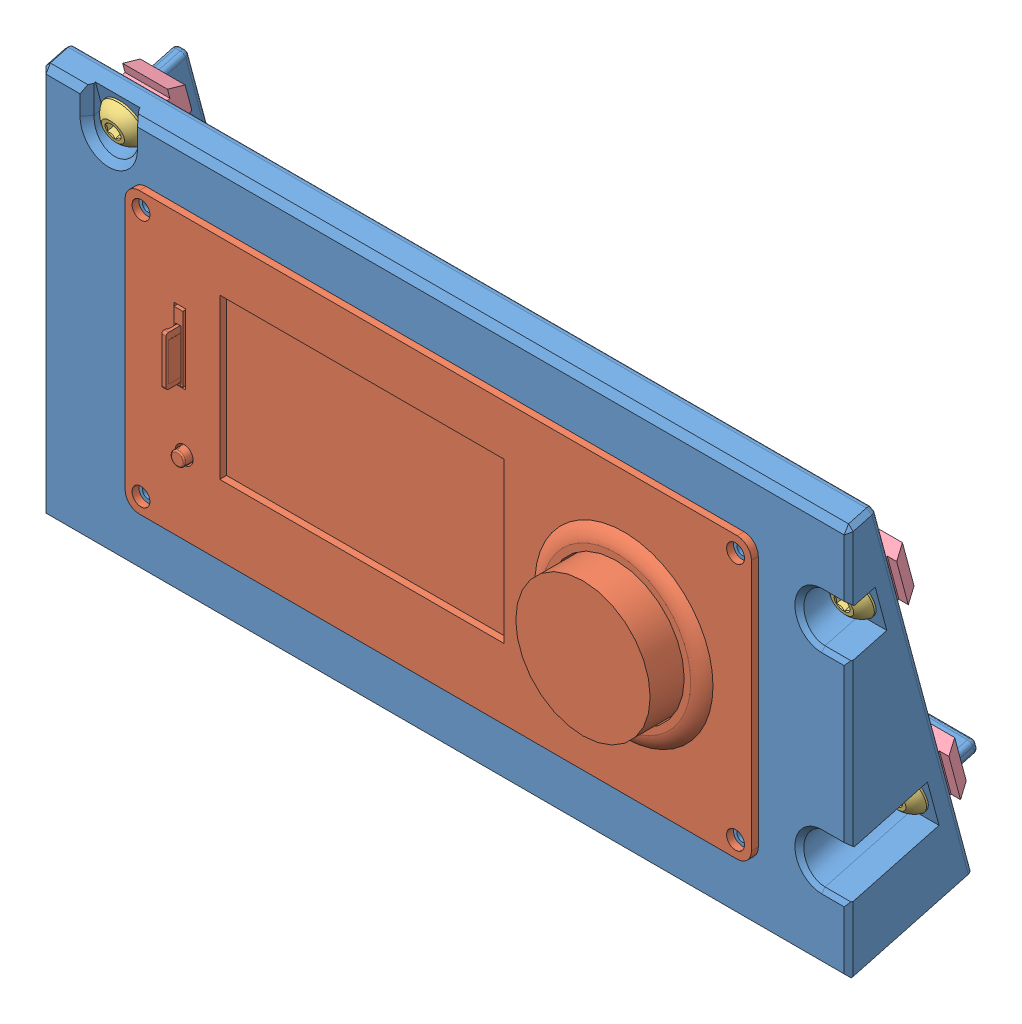
SolidWorks assembly Viki2_LCD_Module, configuration Default. Lengths in mm.
Overall size (180 89.23 58.16).
8 component instances, 4 part files, 18 mates.
Components (placement in the parent):
- Viki2_Mount-1: Viki2_Mount [Default] at origin size (180 88.55 48.84)
- Viki2_LCD-1: Viki2_LCD [Default] at (-111.8203 -17.9312 -4.239) x (1 0.00011 0) z (0 0 1) size (139.71 62.5 29.06)
- 5mmX10mm_Buttonhead(McMaster_91239A224)-1: 5mmX10mm_Buttonhead(McMaster_91239A224) [91239A224] at (-165 -6.7661 2.0693) x (1 0 0) z (0 -0.258819 0.965926) size (9.5 9.5 13.21)
- 5mmX10mm_Buttonhead(McMaster_91239A224)-2: 5mmX10mm_Buttonhead(McMaster_91239A224) [91239A224] at (-6 -20.2891 -1.5542) x (1 0 0) z (0 -0.258819 0.965926) size (9.5 9.5 13.21)
- 5mmX10mm_Buttonhead(McMaster_91239A224)-3: 5mmX10mm_Buttonhead(McMaster_91239A224) [91239A224] at (-6 -63.7572 -13.2014) x (1 0 0) z (0 -0.258819 0.965926) size (9.5 9.5 13.21)
- HNTTSN5-5-1: HNTTSN5-5 [Default] at (-165 -4.7085 -5.6098) x (0 -0.258819 0.965926) z (-1 0 0) size (4.3 10 10)
- HNTTSN5-5-2: HNTTSN5-5 [Default] at (-6 -18.2315 -9.2333) x (0 -0.258819 0.965926) z (0 0.965926 0.258819) size (4.3 10 10)
- HNTTSN5-5-3: HNTTSN5-5 [Default] at (-6 -61.6996 -20.8805) x (0 -0.258819 0.965926) z (0 0.965926 0.258819) size (4.3 10 10)
Mates (geometry in assembly coordinates):
- Coincident1: coincident anti-aligned: plane of Viki2_Mount-1 through (0 0 3) normal (0 0 1); plane of Viki2_LCD-1 through (-20.15 -75.242 3) normal (0 0 -1)
- Coincident2: coincident aligned: plane of Viki2_Mount-1 through (-90 0 0) normal (1 0 0); plane of Viki2_LCD-1
- Coincident3: coincident anti-aligned: plane of Viki2_Mount-1 through (0 -44 0) normal (0 1 0); plane of Viki2_LCD-1
- Concentric1: concentric aligned: cylinder of Viki2_Mount-1 through (-165 -3.1158 -11.554) axis (0 -0.258819 0.965926) radius 2.6; cylinder of 5mmX10mm_Buttonhead(McMaster_91239A224)-1 through (-165 -6.7661 2.0693) axis (0 -0.258819 0.965926) radius 4.75
- Coincident4: coincident anti-aligned: plane of Viki2_Mount-1 through (-165 -6.0544 -0.587) normal (0 -0.258819 0.965926); plane of 5mmX10mm_Buttonhead(McMaster_91239A224)-1 through (-165 -10.6425 -1.8164) normal (0 0.258819 -0.965926)
- Concentric2: concentric anti-aligned: cylinder of 5mmX10mm_Buttonhead(McMaster_91239A224)-1 through (-165 -6.7661 2.0693) axis (0 -0.258819 0.965926) radius 4.75; cylinder of HNTTSN5-5-1 through (-165 -4.7085 -5.6098) axis (0 0.258819 -0.965926) radius 2.067
- Parallel1: parallel aligned: plane of Viki2_Mount-1 through (-180 0 3) normal (-1 0 0); plane of HNTTSN5-5-1 through (-170 -4.7085 -5.6098) normal (-1 0 0)
- Distance1: distance = 2 mm anti-aligned: plane of Viki2_Mount-1 through (-3 -81.3287 -24.8978) normal (0 0.258819 -0.965926); plane of HNTTSN5-5-1 through (-170 -1.7003 -5.632) normal (0 -0.258819 0.965926)
- Concentric3: concentric aligned: cylinder of Viki2_Mount-1 through (-6 -16.6387 -15.1775) axis (0 -0.258819 0.965926) radius 2.6; cylinder of 5mmX10mm_Buttonhead(McMaster_91239A224)-2 through (-6 -20.2891 -1.5542) axis (0 -0.258819 0.965926) radius 4.75
- Coincident7: coincident anti-aligned: plane of Viki2_Mount-1 through (-6 -19.5773 -4.2105) normal (0 -0.258819 0.965926); plane of 5mmX10mm_Buttonhead(McMaster_91239A224)-2 through (-6 -24.1655 -5.4398) normal (0 0.258819 -0.965926)
- Concentric4: concentric anti-aligned: cylinder of 5mmX10mm_Buttonhead(McMaster_91239A224)-2 through (-6 -20.2891 -1.5542) axis (0 -0.258819 0.965926) radius 4.75; cylinder of HNTTSN5-5-2 through (-6 -18.2315 -9.2333) axis (0 0.258819 -0.965926) radius 2.067
- Perpendicular1: perpendicular: plane of Viki2_Mount-1 through (0 0 3) normal (1 0 0); plane of HNTTSN5-5-2 through (-6 -23.0611 -10.5274) normal (0 -0.965926 -0.258819)
- Distance2: distance = 2 mm anti-aligned: plane of HNTTSN5-5-2 through (-3.1 -13.1948 -8.7119) normal (0 -0.258819 0.965926); plane of Viki2_Mount-1 through (-3 -81.3287 -24.8978) normal (0 0.258819 -0.965926)
- Concentric5: concentric aligned: cylinder of Viki2_Mount-1 through (-6 -60.1068 -26.8247) axis (0 -0.258819 0.965926) radius 2.6; cylinder of 5mmX10mm_Buttonhead(McMaster_91239A224)-3 through (-6 -63.7572 -13.2014) axis (0 -0.258819 0.965926) radius 4.75
- Coincident10: coincident anti-aligned: plane of Viki2_Mount-1 through (-6 -63.0454 -15.8577) normal (0 -0.258819 0.965926); plane of 5mmX10mm_Buttonhead(McMaster_91239A224)-3 through (-6 -67.6336 -17.0871) normal (0 0.258819 -0.965926)
- Concentric6: concentric anti-aligned: cylinder of 5mmX10mm_Buttonhead(McMaster_91239A224)-3 through (-6 -63.7572 -13.2014) axis (0 -0.258819 0.965926) radius 4.75; cylinder of HNTTSN5-5-3 through (-6 -61.6996 -20.8805) axis (0 0.258819 -0.965926) radius 2.067
- Perpendicular2: perpendicular: plane of Viki2_Mount-1 through (0 0 3) normal (1 0 0); plane of HNTTSN5-5-3 through (-6 -66.5292 -22.1746) normal (0 -0.965926 -0.258819)
- Distance3: distance = 2 mm anti-aligned: plane of HNTTSN5-5-3 through (-3.1 -56.6629 -20.3592) normal (0 -0.258819 0.965926); plane of Viki2_Mount-1 through (-3 -81.3287 -24.8978) normal (0 0.258819 -0.965926)
